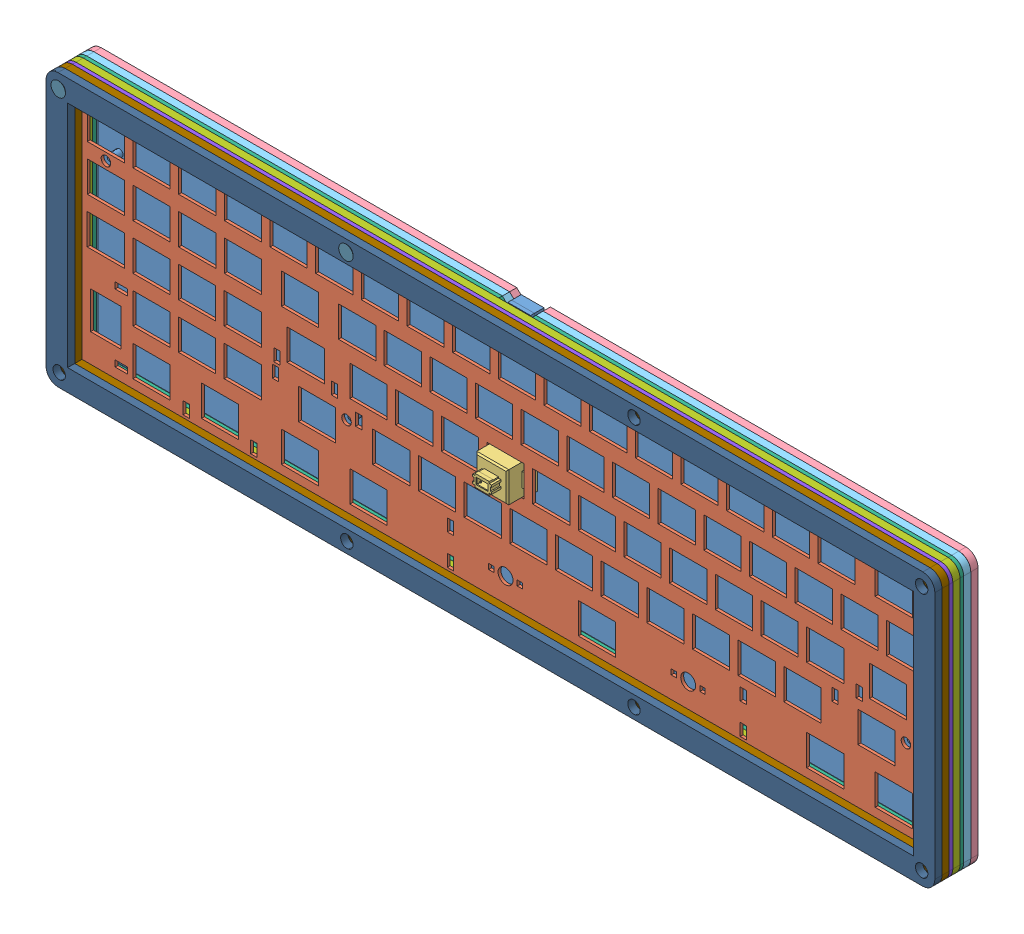
SolidWorks assembly next_assembly, configuration Default. Lengths in mm.
Overall size (370.78 113.6 21.9).
20 component instances, 14 part files, 37 mates.
Components (placement in the parent):
- pcb_next-1: pcb_next [Default] at (0 56.8 6) x (1 0 0) z (0 -1 0) size (351.4 10.1 103.2)
- plate-1: plate [Default] at (-176.8875 4.75 11.7) x (1 0 0) z (0 0 -1) size (353.78 104.1 1.2)
- alps_switch-1: alps_switch [Default] at (0 56.8 17.6) x (0 1 0) z (0 0 -1) size (14.1 17.25 19.55)
- 3mm_matte_1-1: 3mm_matte_1 [Default] at (-185.3875 0 0) size (370.78 113.6 3)
- 3mm_2-1: 3mm_2 [Default] at (-185.3875 0 3) size (370.78 113.6 3)
- 1_5mm_3-1: 1_5mm_3 [Default] at (-185.3875 0 6) size (370.78 113.6 1.5)
- 3mm_4-1: 3mm_4 [Default] at (-185.3875 0 7.5) size (370.78 113.6 3)
- 1_5mm_5-1: 1_5mm_5 [Default] at (-185.3875 0 10.5) size (370.78 113.6 1.5)
- 3mm_6-1: 3mm_6 [Default] at (-185.3875 0 12) size (370.78 113.6 3)
- 3mm_matte_7-1: 3mm_matte_7 [Default] at (-185.3875 0 15) size (370.78 113.6 3)
- hex_spacer-1: hex_spacer [8mm] at (-59.8875 109.1 6) size (5.2 4.5 8)
- hex_spacer-2: hex_spacer [8mm] at (-179.8875 108.1 6) x (0.707107 0.707107 0) z (0 0 1) size (5.2 4.5 8)
- m2_countersunk-1: m2_countersunk [4mm_standoff] at (-100 107.6 -0.35) x (0.999962 -0.008662 0) z (0 0 1) size (4 4 10.35)
- m2_button-1: m2_button [3mm] at (-100 107.6 13) x (0.973037 0.230647 0) z (0 0 -1) size (3.3 3.3 4.24)
- m2_countersunk-2: m2_countersunk [4mm_standoff] at (-10 109.1 -0.35) size (4 4 10.35)
- m2_button-2: m2_button [4mm] at (-10 109.1 13.3) x (-0.923728 -0.383049 0) z (0 0 -1) size (3.3 3.3 5.24)
- m3_countersunk-1: m3_countersunk [8mm] at (-179.8875 108.1 18.4) x (-0.923728 -0.383049 0) z (0 0 -1) size (6 6 8)
- m3_countersunk-2: m3_countersunk [8mm] at (-179.8875 108.1 -0.4) size (6 6 8)
- m3_countersunk-3: m3_countersunk [8mm] at (-59.8875 109.1 18.4) x (-0.923728 -0.383049 0) z (0 0 -1) size (6 6 8)
- m3_countersunk-4: m3_countersunk [8mm] at (-59.8875 108.1 -0.4) size (6 6 8)
Mates (geometry in assembly coordinates):
- Coincident31: coincident aligned: line of 3mm_2-1 through (-185.3875 108.6 3) axis (0 -1 0); line of 3mm_matte_1-1 through (-185.3875 108.6 3) axis (0 -1 0)
- Coincident32: coincident anti-aligned: line of 3mm_2-1 through (180.3875 0 3) axis (-1 0 0); line of 3mm_matte_1-1 through (-180.3875 0 3) axis (1 0 0)
- Coincident33: coincident aligned: line of 1_5mm_3-1 through (-185.3875 108.6 6) axis (0 -1 0); line of 3mm_2-1 through (-185.3875 108.6 6) axis (0 -1 0)
- Coincident34: coincident anti-aligned: line of 1_5mm_3-1 through (-180.3875 0 6) axis (1 0 0); line of 3mm_2-1 through (180.3875 0 6) axis (-1 0 0)
- Coincident35: coincident aligned: line of 1_5mm_3-1 through (-185.3875 108.6 7.5) axis (0 -1 0); line of 3mm_4-1 through (-185.3875 108.6 7.5) axis (0 -1 0)
- Coincident36: coincident aligned: line of 1_5mm_3-1 through (-180.3875 0 7.5) axis (1 0 0); line of 3mm_4-1 through (-180.3875 0 7.5) axis (1 0 0)
- Coincident37: coincident aligned: line of 1_5mm_5-1 through (-185.3875 108.6 10.5) axis (0 -1 0); line of 3mm_4-1 through (-185.3875 108.6 10.5) axis (0 -1 0)
- Coincident38: coincident aligned: line of 1_5mm_5-1 through (-180.3875 0 10.5) axis (1 0 0); line of 3mm_4-1 through (-180.3875 0 10.5) axis (1 0 0)
- Coincident39: coincident anti-aligned: line of 1_5mm_5-1 through (-180.3875 0 12) axis (1 0 0); line of 3mm_6-1 through (180.3875 0 12) axis (-1 0 0)
- Coincident40: coincident aligned: line of 1_5mm_5-1 through (-185.3875 108.6 12) axis (0 -1 0); line of 3mm_6-1 through (-185.3875 108.6 12) axis (0 -1 0)
- Coincident41: coincident aligned: line of 3mm_6-1 through (-185.3875 108.6 15) axis (0 -1 0); line of 3mm_matte_7-1 through (-185.3875 108.6 15) axis (0 -1 0)
- Coincident42: coincident anti-aligned: line of 3mm_6-1 through (180.3875 0 15) axis (-1 0 0); line of 3mm_matte_7-1 through (-180.3875 0 15) axis (1 0 0)
- Width1: width anti-aligned: plane of plate-1 through (-176.8875 4.75 10.5) normal (-1 0 0); plane of 3mm_matte_1-1 through (176.8875 4.75 10.5) normal (1 0 0); plane of plate-1 through (185.3875 108.6 3) normal (1 0 0); plane of 3mm_matte_1-1 through (-185.3875 108.6 3) normal (-1 0 0)
- Width2: width anti-aligned: plane of plate-1 through (-176.8875 105.1 10.5) normal (0 1 0); plane of 3mm_matte_1-1 through (-176.8875 8.5 10.5) normal (0 -1 0); plane of plate-1 through (180.3875 0 3) normal (0 -1 0); plane of 3mm_matte_1-1 through (-180.3875 113.6 3) normal (0 1 0)
- Coincident44: coincident anti-aligned: plane of plate-1 through (-176.8875 4.75 10.5) normal (0 0 -1); plane of 3mm_4-1 through (180.3875 5 10.5) normal (0 0 1)
- Parallel1: parallel anti-aligned: plane of 3mm_matte_1-1 through (180.3875 0 3) normal (0 -1 0); plane of hex_spacer-1 through (-61.1865 111.35 14) normal (0 1 0)
- Coincident49: coincident anti-aligned: plane of 3mm_4-1 through (-62.4856 109.1 10.5) normal (0.866025 0.5 0); plane of hex_spacer-1 through (-62.4856 109.1 14) normal (-0.866025 -0.5 0)
- Coincident50: coincident aligned: circle of 3mm_2-1; circle of hex_spacer-1
- Coincident51: coincident aligned: cone of 3mm_matte_1-1; cone of m2_countersunk-2 through (-10 109.1 -0.35) axis (0 0 1)
- Coincident52: coincident aligned: circle of 3mm_matte_1-1; cone of m2_countersunk-1 through (-100 107.6 -0.35) axis (0 0 1)
- Concentric3: concentric anti-aligned: cylinder of 3mm_matte_1-1 through (-100 107.6 3) axis (0 0 -1) radius 1.65; cylinder of m2_button-1 through (-100 107.6 8.7) axis (0 0 1) radius 0.95
- Coincident54: coincident anti-aligned: plane of 1_5mm_5-1 through (180.3875 5 12) normal (0 0 1); plane of m2_button-2 through (-10 109.1 12) normal (0 0 -1)
- Concentric4: concentric anti-aligned: cylinder of 3mm_matte_1-1 through (-10 109.1 3) axis (0 0 -1) radius 1.65; cylinder of m2_button-2 through (-10 109.1 8) axis (0 0 1) radius 0.95
- Width3: width aligned: plane of alps_switch-1 through (7.7 63.15 6) normal (0 1 0); plane of plate-1 through (7.7 50.45 6) normal (0 -1 0); plane of alps_switch-1 through (-176.8875 50.4 10.5) normal (0 1 0); plane of plate-1 through (-176.8875 63.2 10.5) normal (0 -1 0)
- Width4: width aligned: plane of alps_switch-1 through (-7.7 50.45 6) normal (-1 0 0); plane of plate-1 through (7.7 50.45 6) normal (1 0 0); plane of alps_switch-1 through (7.75 4.75 10.5) normal (-1 0 0); plane of plate-1 through (-7.75 4.75 10.5) normal (1 0 0)
- Width5: width anti-aligned: plane of pcb_next-1 through (4.75 104.4 4.4) normal (0 1 0); plane of plate-1 through (-175.7 9.2 4.4) normal (0 -1 0); plane of pcb_next-1 through (-176.8875 8.5 10.5) normal (0 -1 0); plane of plate-1 through (-176.8875 105.1 10.5) normal (0 1 0)
- Width6: width anti-aligned: plane of plate-1 through (-176.8875 4.75 10.5) normal (-1 0 0); plane of pcb_next-1 through (176.8875 4.75 10.5) normal (1 0 0); plane of plate-1 through (175.7 9.2 4.4) normal (1 0 0); plane of pcb_next-1 through (-175.7 9.2 4.4) normal (-1 0 0)
- Coincident62: coincident anti-aligned: plane of pcb_next-1 through (0 56.8 6) normal (0 0 1); plane of alps_switch-1 through (-7.7 50.45 6) normal (0 0 -1)
- Coincident63: coincident aligned: plane of plate-1 through (-176.8875 4.75 10.5) normal (0 0 -1); plane of alps_switch-1 through (6.925 59.8 10.5) normal (0 0 -1)
- Coincident65: coincident anti-aligned: plane of 3mm_2-1 through (-185.3875 0 6) normal (0 0 1); plane of hex_spacer-2 through (-179.8875 108.1 6) normal (0 0 -1)
- Coincident66: coincident anti-aligned: plane of 1_5mm_3-1 through (-181.7246 106.2629 7.5) normal (0.258819 0.965926 0); plane of hex_spacer-2 through (-181.7246 106.2629 14) normal (-0.258819 -0.965926 0)
- Coincident67: coincident anti-aligned: plane of 1_5mm_3-1 through (-179.2151 105.5905 7.5) normal (-0.707107 0.707107 0); plane of hex_spacer-2 through (-179.2151 105.5905 14) normal (0.707107 -0.707107 0)
- Coincident68: coincident anti-aligned: circle of 3mm_matte_7-1; cone of m3_countersunk-1 through (-179.8875 108.1 18.4) axis (0 0 -1)
- Coincident69: coincident aligned: circle of 3mm_matte_1-1; cone of m3_countersunk-2 through (-179.8875 108.1 -0.4) axis (0 0 1)
- Coincident70: coincident anti-aligned: circle of 3mm_matte_7-1; cone of m3_countersunk-3 through (-59.8875 109.1 18.4) axis (0 0 -1)
- Coincident71: coincident aligned: circle of 3mm_matte_1-1; cone of m3_countersunk-4 through (-59.8875 108.1 -0.4) axis (0 0 1)
- Coincident72: coincident anti-aligned: plane of plate-1 through (-176.8875 4.75 11.7) normal (0 0 1); plane of m2_button-1 through (-100 107.6 11.7) normal (0 0 -1)
